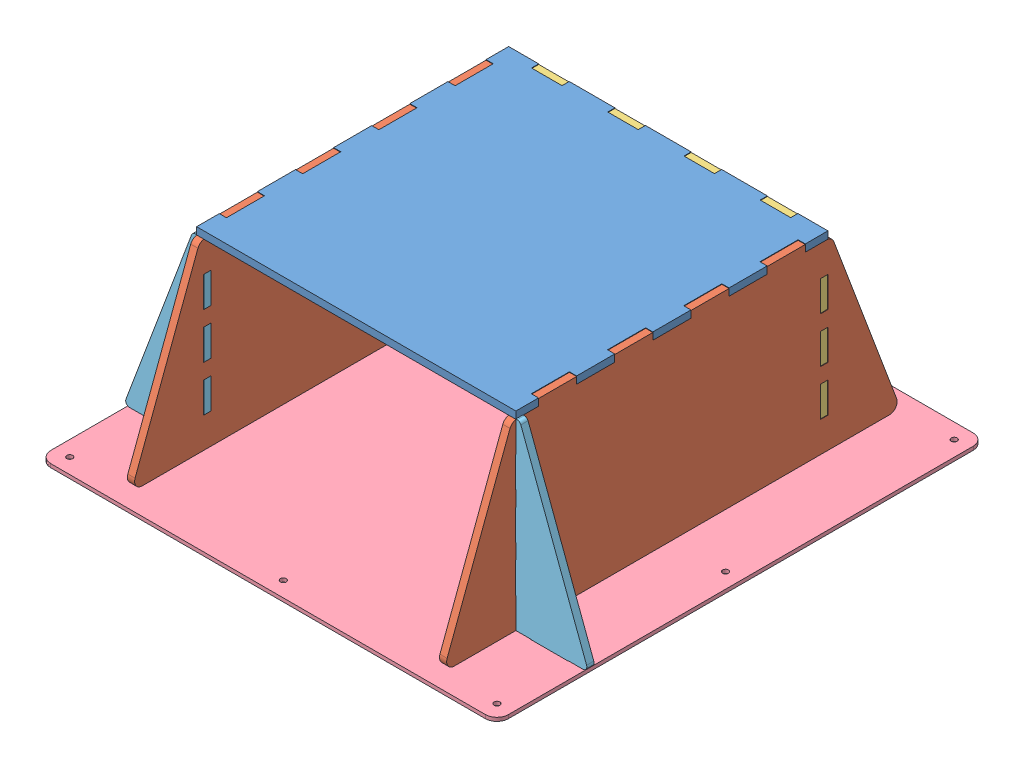
SolidWorks assembly Pillar Assembly, configuration Default. Lengths in mm.
Overall size (384.24 161.45 406.4).
7 component instances, 5 part files, 33 mates.
Components (placement in the parent):
- P001 - Top-1: P001 - Top [Default] at (0 155.4 0) x (0 0 -1) z (1 0 0) size (260 6 266)
- P002 - Side-1: P002 - Side [Default] at (-133 79.2 0) x (0 0 -1) z (0 -1 0) size (375.37 6 160.73)
- P002 - Side-3: P002 - Side [Default] at (127 79.2 0) x (0 0 -1) z (0 -1 0) size (375.37 6 160.73)
- P003 - Front-1: P003 - Front [Default] at (0 79.2 -124) x (-1 0 0) z (0 -1 0) size (265.18 6 160.73)
- P004 - Base-1: P004 - Base [Default] at (-190.7286 0 67.4607) x (0 0 -1) z (0 1 0) size (406.4 381.25 3)
- P005 - Gusset-1: P005 - Gusset [Default] at (-136.2766 79.3016 130) x (-1 0 0) z (0 -1 0) size (65.12 6 155.65)
- P005 - Gusset-2: P005 - Gusset [Default] at (136.2766 79.3016 124) x (1 0 0) z (0 -1 0) size (65.12 6 155.65)
Mates (geometry in assembly coordinates):
- Coincident2: coincident anti-aligned: plane of P002 - Side-1 through (-127 79.2 0) normal (1 0 0); plane of P001 - Top-1 through (-127 123.088 79.375) normal (-1 0 0)
- Coincident3: coincident aligned: plane of P001 - Top-1 through (0 155.4 0) normal (0 0 -1); plane of P002 - Side-1 through (-133 79.2 0) normal (0 0 -1)
- Coincident4: coincident anti-aligned: plane of P001 - Top-1 through (0 155.4 0) normal (0 -1 0); plane of P002 - Side-1 through (-127 155.4 -133.35) normal (0 1 0)
- Coincident6: coincident anti-aligned: plane of P001 - Top-1 through (127 123.088 79.375) normal (1 0 0); plane of P002 - Side-3 through (127 79.2 0) normal (-1 0 0)
- Coincident7: coincident aligned: plane of P001 - Top-1 through (0 155.4 0) normal (0 0 -1); plane of P002 - Side-3 through (127 79.2 0) normal (0 0 -1)
- Coincident11: coincident aligned: plane of P001 - Top-1 through (19.05 123.088 -124) normal (0 0 -1); plane of P003 - Front-1 through (0 79.2 -124) normal (0 0 -1)
- Coincident12: coincident anti-aligned: plane of P001 - Top-1 through (0 155.4 0) normal (0 -1 0); plane of P003 - Front-1 through (127 155.4 -130) normal (0 1 0)
- Coincident13: coincident anti-aligned: plane of P001 - Top-1 through (0 155.4 0) normal (1 0 0); plane of P003 - Front-1 through (0 79.2 -124) normal (-1 0 0)
- Coincident14: coincident anti-aligned: plane of P002 - Side-1 through (-127 3 190.5) normal (0 -1 0); plane of P004 - Side Base-1 through (279.3034 17.3419 7.8046) normal (0 1 0)
- Coincident15: coincident aligned: plane of P001 - Top-1 through (0 155.4 0) normal (0 0 -1); plane of P004 - Side Base-1 through (85.6284 11.3419 36.3796) normal (1 0 0)
- Width1: width anti-aligned: plane of P004 - Side Base-1 through (69.7534 -21.0369 61.7796) normal (0 0 -1); plane of P002 - Side-1 through (69.7534 -21.0369 55.4296) normal (0 0 1); plane of P004 - Side Base-1 through (-127 79.2 0) normal (1 0 0); plane of P002 - Side-1 through (-133 79.2 0) normal (-1 0 0)
- Coincident16: coincident anti-aligned: plane of P004 - Side Base-2 through (279.3034 17.3419 369.4046) normal (0 1 0); plane of P002 - Side-3 through (133 3 190.5) normal (0 -1 0)
- Coincident17: coincident aligned: plane of P001 - Top-1 through (0 155.4 0) normal (0 0 -1); plane of P004 - Side Base-2 through (85.6284 17.3419 340.8296) normal (1 0 0)
- Width2: width anti-aligned: plane of P004 - Side Base-2 through (69.7534 49.7206 315.4296) normal (0 0 1); plane of P004 - Side Base-2 through (69.7534 49.7206 321.7796) normal (0 0 -1); plane of P002 - Side-3 through (127 79.2 0) normal (-1 0 0); plane of P002 - Side-3 through (133 79.2 0) normal (1 0 0)
- Coincident19: coincident aligned: plane of P004 - Side Base-1 through (279.3034 11.3419 7.8046) normal (0 -1 0); plane of P005 - Front Base-1 through (244.3784 11.3419 188.6046) normal (0 -1 0)
- Coincident20: coincident aligned: plane of P001 - Top-1 through (0 155.4 0) normal (1 0 0); plane of P005 - Front Base-1 through (244.3784 11.3419 188.6046) normal (0 0 1)
- Coincident21: coincident aligned: plane of P004 - Side Base-1 through (288.8284 17.3419 74.4796) normal (1 0 0); plane of P005 - Front Base-1 through (288.8284 17.3419 74.3046) normal (1 0 0)
- Coincident22: coincident anti-aligned: plane of P003 - Front-1 through (-111.125 3 -92.1317) normal (-1 0 0); plane of P004 - Base-1 through (-111.125 3 67.4607) normal (1 0 0)
- Coincident23: coincident anti-aligned: plane of P002 - Side-3 through (94.712 3 174.6504) normal (0 0 1); plane of P004 - Base-1 through (132.8293 3 174.6504) normal (0 0 -1)
- Coincident24: coincident anti-aligned: plane of P003 - Front-1 through (127 3 -130) normal (0 -1 0); plane of P004 - Base-1 through (-181.2036 3 -193.548) normal (0 1 0)
- Coincident25: coincident anti-aligned: plane of P002 - Side-1 through (-159.1817 130 130.175) normal (0 -1 0); plane of P002 - Side-4 through (-38.1966 144.3419 185.7796) normal (0 1 0)
- Coincident26: coincident anti-aligned: plane of P002 - Side-1 through (-159.1817 130 130.175) normal (0 0 -1); plane of P002 - Side-4 through (-44.5466 93.5419 185.7796) normal (-1 0 0)
- Coincident27: coincident anti-aligned: plane of P002 - Side-1 through (-133 79.2 0) normal (-1 0 0); plane of P002 - Side-4 through (-38.1966 93.5419 55.6046) normal (0 0 1)
- Coincident31: coincident anti-aligned: plane of P004 - Base-1 through (-181.2036 3 -193.548) normal (0 1 0); plane of P007 - Gusset-1 through (-177.6786 3 298.725) normal (0 -1 0)
- Coincident32: coincident anti-aligned: plane of P002 - Side-1 through (-133 79.2 0) normal (-1 0 0); plane of P007 - Gusset-1 through (-133 155.6032 298.725) normal (1 0 0)
- Width4: width anti-aligned: plane of P007 - Gusset-1 through (-136.2766 79.3016 130) normal (0 0 1); plane of P007 - Gusset-1 through (-136.2766 79.3016 124) normal (0 0 -1); plane of P002 - Side-1 through (-159.1817 130 130.175) normal (0 0 -1); plane of P002 - Side-1 through (-159.1817 130 123.825) normal (0 0 1)
- Coincident33: coincident aligned: plane of assembly through (0 0 0) normal (1 0 0); plane of P001 - Top-1 through (0 155.4 0) normal (1 0 0)
- Coincident34: coincident anti-aligned: plane of P001 - Top-1 through (0 155.4 0) normal (0 0 -1)
- Coincident35: coincident anti-aligned: plane of P004 - Base-1 through (-181.2036 0 -193.548) normal (0 -1 0)
- Coincident36: coincident anti-aligned: plane of P001 - Top-1 through (0 155.4 0) normal (0 -1 0); plane of P002 - Side-3 through (133 155.4 -133.35) normal (0 1 0)
- Width5: width anti-aligned: plane of P007 - Gusset-2 through (136.2766 79.3016 130) normal (0 0 1); plane of P007 - Gusset-2 through (136.2766 79.3016 124) normal (0 0 -1); plane of P002 - Side-3 through (100.8183 130 123.825) normal (0 0 1); plane of P002 - Side-3 through (100.8183 130 130.175) normal (0 0 -1)
- Coincident37: coincident anti-aligned: plane of P004 - Base-1 through (-181.2036 3 -193.548) normal (0 1 0); plane of P007 - Gusset-2 through (177.6786 3 -44.725) normal (0 -1 0)
- Coincident38: coincident anti-aligned: plane of P002 - Side-3 through (133 79.2 0) normal (1 0 0); plane of P007 - Gusset-2 through (133 104.6 -44.725) normal (-1 0 0)
